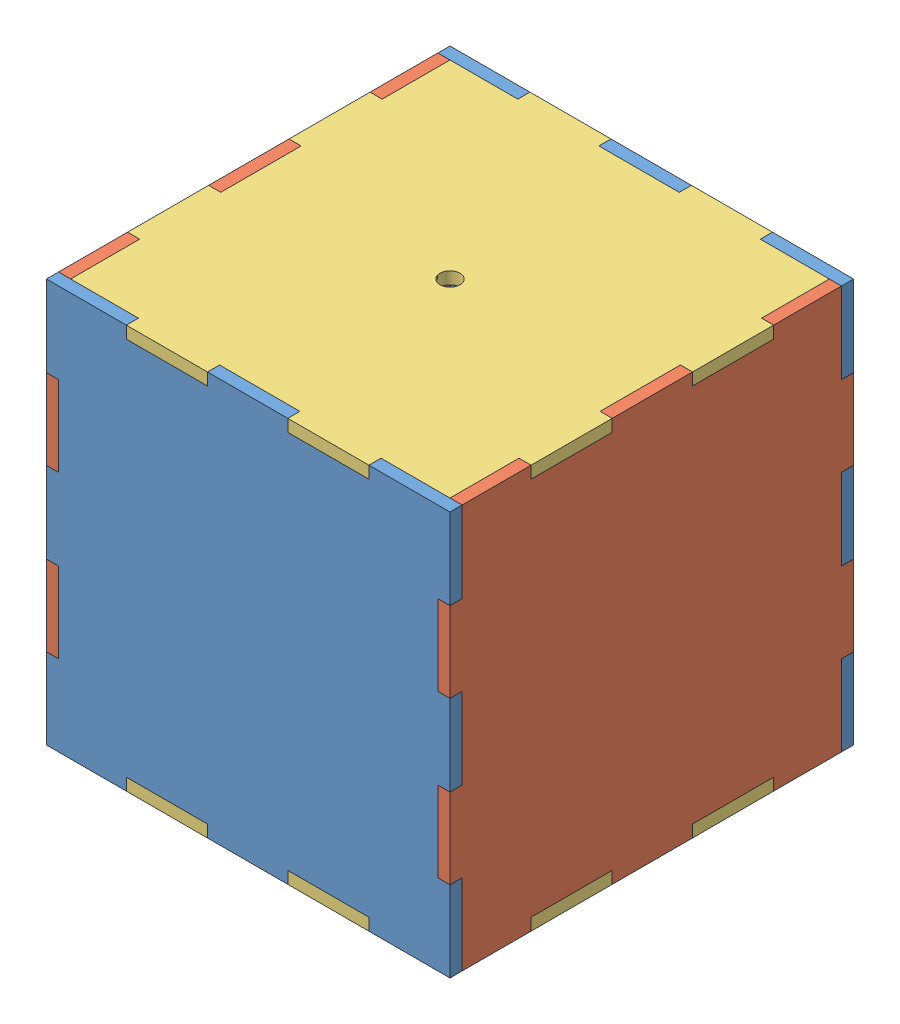
SolidWorks assembly 1u SAT, configuration Default. Lengths in mm.
Overall size (100 100 100).
7 component instances, 4 part files, 15 mates.
Components (placement in the parent):
- SAT Side 1(10cm)-1: SAT Side 1(10cm) [Default] at (-20.815 1.3616 80.1149) size (100 100 3)
- SAT Side 2(10cm)-1: SAT Side 2(10cm) [Default] at (-17.815 1.3616 -16.8851) x (0 0 1) z (-1 0 0) size (100 100 3)
- SAT Top Bottom(10cm)-1: SAT Top Bottom(10cm) [Default] at (-20.815 1.3616 83.1149) size (100 3 100)
- Part6^1u SAT-1: Part6^1u SAT [Default] at origin (virtual)
- SAT Side 1(10cm)-2: SAT Side 1(10cm) [Default] at (-20.815 1.3616 -16.8851) size (100 100 3)
- SAT Side 2(10cm)-2: SAT Side 2(10cm) [Default] at (79.185 1.3616 -16.8851) x (0 0 1) z (-1 0 0) size (100 100 3)
- SAT Top Bottom(10cm)-2: SAT Top Bottom(10cm) [Default] at (-20.815 98.3616 83.1149) size (100 3 100)
Mates (geometry in assembly coordinates):
- Coincident1: coincident aligned: plane of SAT Side 1(10cm)-1 through (-20.815 1.3616 83.1149) normal (0 -1 0); plane of SAT Top Bottom(10cm)-1 through (-20.815 1.3616 83.1149) normal (0 -1 0)
- Coincident2: coincident aligned: plane of SAT Side 1(10cm)-1 through (-20.815 1.3616 83.1149) normal (0 0 1); plane of SAT Top Bottom(10cm)-1 through (-20.815 4.3616 83.1149) normal (0 0 1)
- Coincident3: coincident aligned: plane of SAT Side 1(10cm)-1 through (79.185 1.3616 83.1149) normal (1 0 0); plane of SAT Top Bottom(10cm)-1 through (79.185 4.3616 83.1149) normal (1 0 0)
- Coincident4: coincident anti-aligned: plane of SAT Side 2(10cm)-1 through (-17.815 1.3616 -16.8851) normal (1 0 0); plane of SAT Top Bottom(10cm)-1 through (-17.815 4.3616 83.1149) normal (-1 0 0)
- Coincident5: coincident aligned: plane of SAT Side 2(10cm)-1 through (-20.815 1.3616 -16.8851) normal (0 0 -1); plane of SAT Top Bottom(10cm)-1 through (-20.815 4.3616 -16.8851) normal (0 0 -1)
- Coincident6: coincident aligned: plane of SAT Side 2(10cm)-1 through (-20.815 1.3616 -16.8851) normal (0 -1 0); plane of SAT Top Bottom(10cm)-1 through (-20.815 1.3616 83.1149) normal (0 -1 0)
- Coincident7: coincident anti-aligned: plane of SAT Side 2(10cm)-1 through (-20.815 98.3616 -16.8851) normal (0 1 0); plane of SAT Top Bottom(10cm)-2 through (-20.815 98.3616 83.1149) normal (0 -1 0)
- Coincident8: coincident aligned: plane of SAT Side 2(10cm)-1 through (-20.815 1.3616 -16.8851) normal (-1 0 0); plane of SAT Top Bottom(10cm)-2 through (-20.815 101.3616 83.1149) normal (-1 0 0)
- Coincident9: coincident anti-aligned: plane of SAT Side 1(10cm)-1 through (-20.815 1.3616 80.1149) normal (0 0 -1); plane of SAT Top Bottom(10cm)-2 through (-20.815 101.3616 80.1149) normal (0 0 1)
- Coincident10: coincident anti-aligned: plane of SAT Side 2(10cm)-1 through (-20.815 1.3616 -13.8851) normal (0 0 -1); plane of SAT Side 1(10cm)-2 through (-20.815 1.3616 -13.8851) normal (0 0 1)
- Coincident11: coincident anti-aligned: plane of SAT Side 1(10cm)-2 through (-20.815 98.3616 -13.8851) normal (0 1 0); plane of SAT Top Bottom(10cm)-2 through (-20.815 98.3616 83.1149) normal (0 -1 0)
- Coincident12: coincident aligned: plane of SAT Side 2(10cm)-1 through (-20.815 1.3616 -16.8851) normal (-1 0 0); plane of SAT Side 1(10cm)-2 through (-20.815 1.3616 -13.8851) normal (-1 0 0)
- Coincident13: coincident: plane of SAT Side 1(10cm)-2 through (76.185 1.3616 -13.8851) normal (1 0 0); plane of SAT Side 2(10cm)-2 through (76.185 1.3616 -4.282) normal (-1 0 0)
- Coincident15: coincident: plane of SAT Top Bottom(10cm)-1 through (-20.815 1.3616 83.1149) normal (0 -1 0); plane of SAT Side 2(10cm)-2 through (76.185 1.3616 -16.8851) normal (0 -1 0)
- Coincident16: coincident aligned: plane of SAT Side 1(10cm)-2 through (-20.815 1.3616 -16.8851) normal (0 0 -1); plane of SAT Side 2(10cm)-2 through (76.185 1.3616 -16.8851) normal (0 0 -1)
